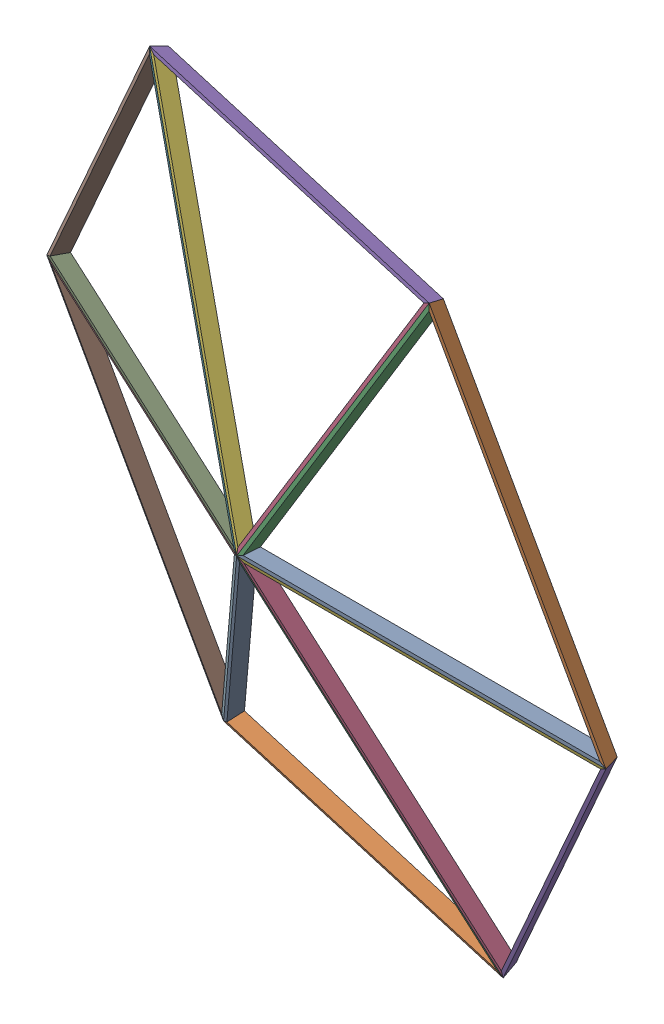
SolidWorks assembly hex_2, configuration Default. Lengths in mm.
Overall size (6834.31 7311.38 4287.38).
24 component instances, 3 part files, 0 mates.
Components (placement in the parent):
- hex_1_1-1: hex_1_1 [Default] at origin size (3132.81 3334.25 2398.03)
  - dome-hex_A_1-1: dome-hex_A_1 [Default] at (-54.8338 723.4273 -6076.5179) x (-0.072057 -0.575985 0.814278) z (-0.865209 0.442256 0.236269) size (283.93 1314.1 2231.51)
  - dome-hex_B_1-1: dome-hex_B_1 [Default] at (-54.8338 723.4273 -6076.5179) x (-0.072057 -0.575985 0.814278) z (-0.865209 0.442256 0.236269) size (1246.15 959.88 2041.73)
  - dome-hex_C_1-1: dome-hex_C_1 [Default] at (-54.8338 723.4273 -6076.5179) x (-0.072057 -0.575985 0.814278) z (-0.865209 0.442256 0.236269) size (1432 2214.62 244.45)
- hex_1_1-2: hex_1_1 [Default] at (-643.6223 1147.3164 0) x (0.52126 0.853398 0) z (-0.200359 0.122381 0.972049) size (3132.81 3334.25 2398.03)
  - dome-hex_A_1-1: dome-hex_A_1 [Default] at (-54.8338 723.4273 -6076.5179) x (-0.072057 -0.575985 0.814278) z (-0.865209 0.442256 0.236269) size (283.93 1314.1 2231.51)
  - dome-hex_B_1-1: dome-hex_B_1 [Default] at (-54.8338 723.4273 -6076.5179) x (-0.072057 -0.575985 0.814278) z (-0.865209 0.442256 0.236269) size (1246.15 959.88 2041.73)
  - dome-hex_C_1-1: dome-hex_C_1 [Default] at (-54.8338 723.4273 -6076.5179) x (-0.072057 -0.575985 0.814278) z (-0.865209 0.442256 0.236269) size (1432 2214.62 244.45)
- hex_1_1-3: hex_1_1 [Default] at (-1930.867 1179.3851 -269.3649) x (-0.436219 0.877251 -0.200359) z (-0.400718 0.009983 0.916147) size (3132.81 3334.25 2398.03)
  - dome-hex_A_1-1: dome-hex_A_1 [Default] at (-54.8338 723.4273 -6076.5179) x (-0.072057 -0.575985 0.814278) z (-0.865209 0.442256 0.236269) size (283.93 1314.1 2231.51)
  - dome-hex_B_1-1: dome-hex_B_1 [Default] at (-54.8338 723.4273 -6076.5179) x (-0.072057 -0.575985 0.814278) z (-0.865209 0.442256 0.236269) size (1246.15 959.88 2041.73)
  - dome-hex_C_1-1: dome-hex_C_1 [Default] at (-54.8338 723.4273 -6076.5179) x (-0.072057 -0.575985 0.814278) z (-0.865209 0.442256 0.236269) size (1432 2214.62 244.45)
- hex_1_1-4: hex_1_1 [Default] at (-2574.4893 64.1374 -538.7298) x (-0.914958 0.047707 -0.400718) z (-0.400718 -0.224795 0.888196) size (3132.81 3334.25 2398.03)
  - dome-hex_A_1-1: dome-hex_A_1 [Default] at (-54.8338 723.4273 -6076.5179) x (-0.072057 -0.575985 0.814278) z (-0.865209 0.442256 0.236269) size (283.93 1314.1 2231.51)
  - dome-hex_B_1-1: dome-hex_B_1 [Default] at (-54.8338 723.4273 -6076.5179) x (-0.072057 -0.575985 0.814278) z (-0.865209 0.442256 0.236269) size (1246.15 959.88 2041.73)
  - dome-hex_C_1-1: dome-hex_C_1 [Default] at (-54.8338 723.4273 -6076.5179) x (-0.072057 -0.575985 0.814278) z (-0.865209 0.442256 0.236269) size (1432 2214.62 244.45)
- hex_1_1-5: hex_1_1 [Default] at (-1930.867 -1083.179 -538.7298) x (-0.436219 -0.805691 -0.400718) z (-0.200359 -0.347176 0.916147) size (3132.81 3334.25 2398.03)
  - dome-hex_A_1-1: dome-hex_A_1 [Default] at (-54.8338 723.4273 -6076.5179) x (-0.072057 -0.575985 0.814278) z (-0.865209 0.442256 0.236269) size (283.93 1314.1 2231.51)
  - dome-hex_B_1-1: dome-hex_B_1 [Default] at (-54.8338 723.4273 -6076.5179) x (-0.072057 -0.575985 0.814278) z (-0.865209 0.442256 0.236269) size (1246.15 959.88 2041.73)
  - dome-hex_C_1-1: dome-hex_C_1 [Default] at (-54.8338 723.4273 -6076.5179) x (-0.072057 -0.575985 0.814278) z (-0.865209 0.442256 0.236269) size (1432 2214.62 244.45)
- hex_1_1-6: hex_1_1 [Default] at (-643.6223 -1115.2477 -269.3649) x (0.52126 -0.829544 -0.200359) z (0 -0.234778 0.972049) size (3132.81 3334.25 2398.03)
  - dome-hex_A_1-1: dome-hex_A_1 [Default] at (-54.8338 723.4273 -6076.5179) x (-0.072057 -0.575985 0.814278) z (-0.865209 0.442256 0.236269) size (283.93 1314.1 2231.51)
  - dome-hex_B_1-1: dome-hex_B_1 [Default] at (-54.8338 723.4273 -6076.5179) x (-0.072057 -0.575985 0.814278) z (-0.865209 0.442256 0.236269) size (1246.15 959.88 2041.73)
  - dome-hex_C_1-1: dome-hex_C_1 [Default] at (-54.8338 723.4273 -6076.5179) x (-0.072057 -0.575985 0.814278) z (-0.865209 0.442256 0.236269) size (1432 2214.62 244.45)
